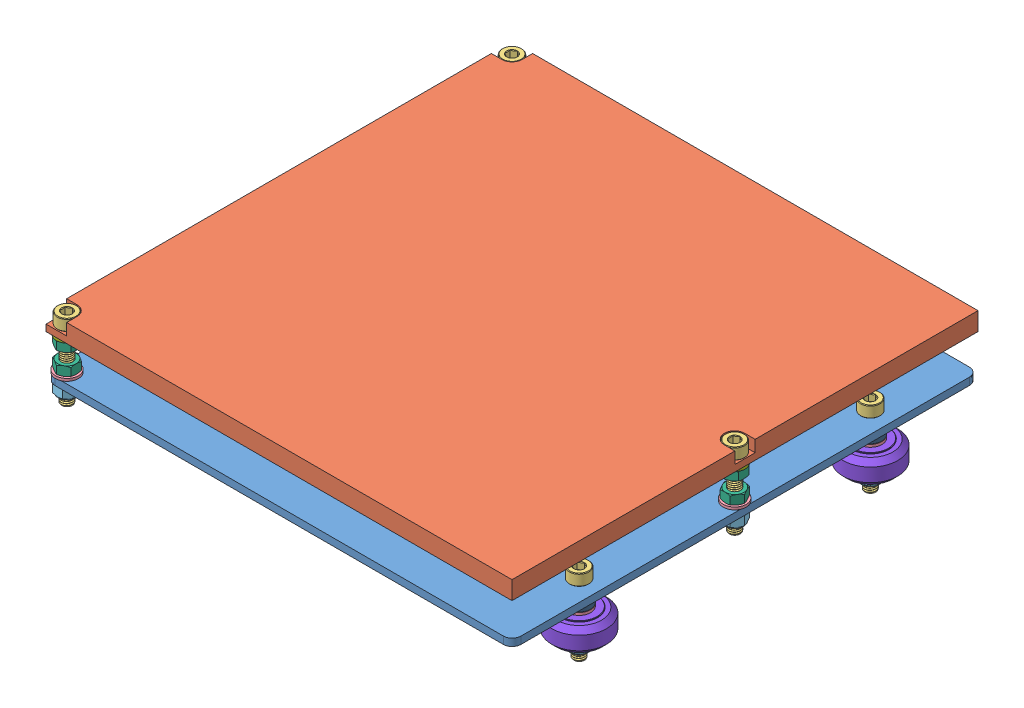
SolidWorks assembly Y-101, configuration Default. Lengths in mm.
Overall size (210.29 53.63 206.16).
50 component instances, 13 part files, 60 mates.
Components (placement in the parent):
- Y-004_rB-1: Y-004_rB [Default] at (-78.9779 0.4223 88.2972) size (203.2 3.17 203.2)
- Y-003-1: Y-003 [Default] at (124.1509 18.8373 -114.9028) x (-1 0 0) z (0 0 -1) size (203.2 7.94 203.2)
- H-017-2: H-017 [91290A194] at (-74.4771 -8.3052 83.7252) x (1 0 0) z (0 -1 0) size (8.5 8.5 35.53)
- H-011-1: H-011 [93475A240] at (-74.4771 4.6973 83.7252) x (1 0 0) z (0 -1 0) size (10 10 1.1)
- H-012-1: H-012 [90576A104] at (-74.4771 0.4223 83.7252) x (-0.837169 0 -0.546944) z (-0.546944 0 0.837169) size (8 5.15 9.24)
- H-016-1: H-016 [92497A300] at (-74.4771 6.6973 83.7252) x (1 0 0) z (0 -1 0) size (8 9.24 4.46)
- H-016-2: H-016 [92497A300] at (-74.4771 15.7373 83.7252) x (1 0 0) z (0 -1 0) size (8 9.24 4.46)
- H-018-1: H-018 [93475A240] at (-74.4771 17.7373 83.7252) x (1 0 0) z (0 1 0) size (9.2 9.2 1.1)
- H-018-2: H-018 [93475A240] at (-74.4771 18.8373 -110.3308) x (1 0 0) z (0 -1 0) size (9.2 9.2 1.1)
- H-016-3: H-016 [92497A300] at (-74.4771 6.6973 -110.3308) x (1 0 0) z (0 -1 0) size (8 9.24 4.46)
- H-016-4: H-016 [92497A300] at (-74.4771 15.7373 -110.3308) x (1 0 0) z (0 -1 0) size (8 9.24 4.46)
- H-012-2: H-012 [90576A104] at (-74.4771 0.4223 -110.3308) x (0.837169 0 -0.546944) z (-0.546944 0 -0.837169) size (8 5.15 9.24)
- H-011-2: H-011 [93475A240] at (-74.4771 3.5973 -110.3308) x (1 0 0) z (0 1 0) size (10 10 1.1)
- H-017-3: H-017 [91290A194] at (-74.4771 -8.3052 -110.3308) x (1 0 0) z (0 -1 0) size (8.5 8.5 35.53)
- H-017-4: H-017 [91290A194] at (119.672 -8.3052 -13.3028) x (1 0 0) z (0 -1 0) size (8.5 8.5 35.53)
- H-011-3: H-011 [93475A240] at (119.672 4.6973 -13.3028) x (1 0 0) z (0 -1 0) size (10 10 1.1)
- H-012-3: H-012 [90576A104] at (119.672 0.4223 -13.3028) x (-0.837169 0 -0.546944) z (-0.546944 0 0.837169) size (8 5.15 9.24)
- H-016-5: H-016 [92497A300] at (119.672 6.6973 -13.3028) x (-0.837169 0 -0.546944) z (0 1 0) size (8 9.24 4.46)
- H-016-6: H-016 [92497A300] at (119.5789 15.7373 -13.3028) x (1 0 0) z (0 -1 0) size (8 9.24 4.46)
- H-018-3: H-018 [93475A240] at (119.5789 18.8373 -13.3028) x (-1 0 0) z (0 -1 0) size (9.2 9.2 1.1)
- H-014-1: H-014 [Default] at (115.3206 -12.1777 50.1972) x (0 1 0) z (0 0 1) size (11 23.9 23.9)
- H-014-4: H-014 [Default] at (-69.4835 -12.1777 50.7192) x (0 -1 0) z (0.98979 0 0.142531) size (11 23.9 23.9)
- H-017-5: H-017 [91290A194] at (115.3206 -26.4027 50.1972) x (1 0 0) z (0 -1 0) size (8.5 8.5 35.53)
- H-002-1: H-002 [Default] at (-70.0765 0.4223 50.1972) x (-0.660682 0 0.750666) z (0.750666 0 0.660682) size (11.55 8.5 10)
- H-003-1: H-003 [Default] at (115.3206 0.4223 50.1972) x (-1 0 0) z (0 -1 0) size (10 10 6)
- H-011-4: H-011 [93475A240] at (115.3206 -6.6777 50.1972) x (-0.837169 0 -0.546944) z (0 1 0) size (10 10 1.1)
- H-012-4: H-012 [90576A104] at (115.3206 -17.6777 50.1972) x (-0.837169 0 -0.546944) z (-0.546944 0 0.837169) size (8 5.15 9.24)
- H-017-6: H-017 [91290A194] at (-69.4835 -26.4027 50.7192) x (0.142531 0 -0.98979) z (0 -1 0) size (8.5 8.5 35.53)
- H-012-5: H-012 [90576A104] at (-69.4835 -17.6777 50.7192) x (-0.861791 0 -0.507263) z (-0.507263 0 0.861791) size (8 5.15 9.24)
- H-011-5: H-011 [93475A240] at (-69.4835 -6.6777 50.7192) x (-0.861791 0 -0.507263) z (0 1 0) size (10 10 1.1)
- H-014-5: H-014 [Default] at (115.3206 -12.1777 -76.8028) x (0 1 0) z (0 0 1) size (11 23.9 23.9)
- H-014-6: H-014 [Default] at (-69.4835 -12.1777 -77.3247) x (0 -1 0) z (-0.98979 0 0.142531) size (11 23.9 23.9)
- H-017-7: H-017 [91290A194] at (115.3206 -26.4027 -76.8028) x (1 0 0) z (0 -1 0) size (8.5 8.5 35.53)
- H-002-2: H-002 [Default] at (-70.0765 0.4223 -76.8028) x (0.660682 0 0.750666) z (0.750666 0 -0.660682) size (11.55 8.5 10)
- H-003-2: H-003 [Default] at (115.3206 -5.5777 -76.8028) x (-1 0 0) z (0 1 0) size (10 10 6)
- H-011-6: H-011 [93475A240] at (115.3206 -5.5777 -76.8028) x (-0.837169 0 0.546944) z (0 -1 0) size (10 10 1.1)
- H-012-6: H-012 [90576A104] at (115.3206 -17.6777 -76.8028) x (0.837169 0 -0.546944) z (-0.546944 0 -0.837169) size (8 5.15 9.24)
- H-017-8: H-017 [91290A194] at (-69.4835 -26.4027 -77.3247) x (0.142531 0 0.98979) z (0 -1 0) size (8.5 8.5 35.53)
- H-012-7: H-012 [90576A104] at (-69.4835 -17.6777 -77.3247) x (0.861791 0 -0.507263) z (-0.507263 0 -0.861791) size (8 5.15 9.24)
- H-011-7: H-011 [93475A240] at (-69.4835 -5.5777 -77.3247) x (-0.861791 0 0.507263) z (0 -1 0) size (10 10 1.1)
- PX-003-1: PX-003 [Default] at (32.6221 -0.8477 9.4772) x (0 0 -1) z (1 0 0) size (8 4 20)
- H-019-1: H-019 [90576A102] at (15.6221 -4.8477 4.4772) x (-0.837169 0 -0.546944) z (-0.546944 0 0.837169) size (5.5 4.1 6.35)
- H-021-1: H-021 [91239A117] at (15.6221 5.2473 4.4772) x (1 0 0) z (0 1 0) size (5.7 5.7 13.97)
- H-021-2: H-021 [91239A117] at (29.6221 5.2473 4.4772) x (1 0 0) z (0 1 0) size (5.7 5.7 13.97)
- H-019-2: H-019 [90576A102] at (29.6221 -4.8477 4.4772) x (-0.837169 0 -0.546944) z (-0.546944 0 0.837169) size (5.5 4.1 6.35)
- PX-003-2: PX-003 [Default] at (12.6221 -0.8477 -36.0828) x (0 0 1) z (-1 0 0) size (8 4 20)
- H-019-3: H-019 [90576A102] at (29.6221 -4.8477 -31.0828) x (0.837169 0 -0.546944) z (-0.546944 0 -0.837169) size (5.5 4.1 6.35)
- H-019-4: H-019 [90576A102] at (15.6221 -4.8477 -31.0828) x (0.837169 0 -0.546944) z (-0.546944 0 -0.837169) size (5.5 4.1 6.35)
- H-021-3: H-021 [91239A117] at (15.6221 5.2473 -31.0828) x (1 0 0) z (0 1 0) size (5.7 5.7 13.97)
- H-021-4: H-021 [91239A117] at (29.6221 5.2473 -31.0828) x (1 0 0) z (0 1 0) size (5.7 5.7 13.97)
Mates (geometry in assembly coordinates):
- Parallel1: parallel aligned: plane of Y-004_rB-1 through (-78.9779 3.5973 88.2972) normal (-1 0 0); plane of Y-003-1 through (-79.0491 26.7748 -114.9028) normal (-1 0 0)
- Coincident2: coincident aligned: plane of Y-004_rB-1 through (-78.9779 3.5973 88.2972) normal (0 0 1); plane of Y-003-1 through (124.1509 26.7748 88.2972) normal (0 0 1)
- Concentric1: concentric anti-aligned: cylinder of Y-004_rB-1 through (-74.4771 3.5983 83.7252) axis (0 -1 0) radius 2.625; cylinder of Y-003-1 through (-74.4771 18.8363 83.7252) axis (0 1 0) radius 2.6098
- Concentric2: concentric anti-aligned: circle of Y-004_rB-1; circle of H-017-2
- Concentric5: concentric anti-aligned: circle of Y-004_rB-1; circle of H-011-1
- Coincident3: coincident anti-aligned: plane of Y-003-1 through (-74.4771 21.6948 83.7252) normal (0 1 0); plane of H-017-2 through (-74.4771 21.6948 83.7252) normal (0 -1 0)
- Coincident4: coincident anti-aligned: plane of Y-004_rB-1 through (-78.9779 3.5973 88.2972) normal (0 1 0); plane of H-011-1 through (-74.4771 3.5973 83.7252) normal (0 -1 0)
- Coincident5: coincident anti-aligned: plane of H-011-1 through (-74.4771 4.6973 83.7252) normal (0 1 0); plane of H-016-1 through (-78.4771 4.6973 86.0346) normal (0 -1 0)
- Concentric6: concentric anti-aligned: circle of H-011-1; circle of H-016-1
- Coincident6: coincident anti-aligned: plane of Y-004_rB-1 through (-78.9779 0.4223 88.2972) normal (0 -1 0); plane of H-012-1 through (-67.3391 0.4223 80.1129) normal (0 1 0)
- Concentric7: concentric anti-aligned: circle of Y-004_rB-1; circle of H-012-1
- Concentric8: concentric aligned: circle of Y-003-1; circle of H-016-2
- Distance1: distance = 15.24 mm anti-aligned: plane of Y-003-1 through (124.1509 18.8373 -114.9028) normal (0 -1 0); plane of Y-004_rB-1 through (-78.9779 3.5973 88.2972) normal (0 1 0)
- Concentric9: concentric aligned: circle of Y-003-1; circle of H-018-1
- Coincident7: coincident anti-aligned: plane of Y-003-1 through (124.1509 18.8373 -114.9028) normal (0 -1 0); plane of H-018-1 through (-74.4771 18.8373 83.7252) normal (0 1 0)
- Coincident8: coincident anti-aligned: plane of H-016-2 through (-78.4771 17.7373 86.0346) normal (0 1 0); plane of H-018-1 through (-74.4771 17.7373 83.7252) normal (0 -1 0)
- Concentric10: concentric aligned: cylinder of Y-004_rB-1 through (119.672 3.5983 -13.3028) axis (0 -1 0) radius 2.625; circle of H-017-4
- Coincident9: coincident anti-aligned: plane of Y-003-1 through (119.5789 21.6948 -13.3028) normal (0 1 0); plane of H-017-4 through (119.672 21.6948 -13.3028) normal (0 -1 0)
- Concentric11: concentric anti-aligned: circle of Y-003-1; circle of H-018-3
- Coincident10: coincident anti-aligned: plane of Y-003-1 through (124.1509 18.8373 -114.9028) normal (0 -1 0); plane of H-018-3 through (119.5789 18.8373 -13.3028) normal (0 1 0)
- Concentric12: concentric anti-aligned: circle of H-017-4; circle of H-012-3
- Coincident11: coincident anti-aligned: plane of Y-004_rB-1 through (-78.9779 0.4223 88.2972) normal (0 -1 0); plane of H-012-3 through (126.8101 0.4223 -16.9151) normal (0 1 0)
- Coincident12: coincident anti-aligned: plane of Y-004_rB-1 through (-78.9779 3.5973 88.2972) normal (0 1 0); plane of H-011-3 through (119.672 3.5973 -13.3028) normal (0 -1 0)
- Concentric13: concentric anti-aligned: circle of Y-004_rB-1; circle of H-011-3
- Coincident13: coincident anti-aligned: plane of H-011-3 through (119.672 4.6973 -13.3028) normal (0 1 0); plane of H-016-5 through (121.7576 4.6973 -9.1816) normal (0 -1 0)
- Concentric14: concentric aligned: circle of H-011-3; circle of H-016-5
- Concentric15: concentric aligned: circle of H-016-6; circle of H-018-3
- Coincident14: coincident anti-aligned: plane of H-016-6 through (115.5789 17.7373 -10.9934) normal (0 1 0); plane of H-018-3 through (119.5789 17.7373 -13.3028) normal (0 -1 0)
- Concentric16: concentric anti-aligned: circle of Y-004_rB-1; circle of H-017-5
- Coincident15: coincident anti-aligned: plane of Y-004_rB-1 through (-78.9779 3.5973 88.2972) normal (0 1 0); plane of H-017-5 through (115.3206 3.5973 50.1972) normal (0 -1 0)
- Concentric17: concentric anti-aligned: circle of H-014-1; circle of H-017-5
- Concentric18: concentric aligned: circle of Y-004_rB-1; circle of H-003-1
- Coincident16: coincident anti-aligned: plane of Y-004_rB-1 through (-78.9779 0.4223 88.2972) normal (0 -1 0); plane of H-003-1 through (112.5706 0.4223 50.1972) normal (0 1 0)
- Coincident17: coincident anti-aligned: plane of H-003-1 through (110.5206 -5.5777 50.1972) normal (0 -1 0); plane of H-011-4 through (115.3206 -5.5777 50.1972) normal (0 1 0)
- Concentric20: concentric aligned: circle of H-003-1; circle of H-011-4
- Concentric21: concentric anti-aligned: circle of H-014-1; circle of H-011-4
- Coincident18: coincident anti-aligned: plane of H-014-1 through (115.3206 -6.6777 50.1972) normal (0 1 0); plane of H-011-4 through (115.3206 -6.6777 50.1972) normal (0 -1 0)
- Concentric22: concentric anti-aligned: circle of H-014-1; circle of H-012-4
- Coincident19: coincident anti-aligned: plane of H-014-1 through (115.3206 -17.6777 50.1972) normal (0 -1 0); plane of H-012-4 through (122.4586 -17.6777 46.5849) normal (0 1 0)
- Coincident21: coincident anti-aligned: plane of Y-004_rB-1 through (-78.9779 3.5973 88.2972) normal (0 1 0); plane of H-017-6 through (-69.4835 3.5973 50.7192) normal (0 -1 0)
- Concentric24: concentric anti-aligned: circle of Y-004_rB-1; circle of H-002-1
- Coincident22: coincident anti-aligned: plane of Y-004_rB-1 through (-78.9779 0.4223 88.2972) normal (0 -1 0); plane of H-002-1 through (-70.0765 0.4223 50.1972) normal (0 1 0)
- Concentric25: concentric anti-aligned: circle of H-014-4; circle of H-002-1
- Concentric26: concentric anti-aligned: circle of H-002-1; circle of H-017-6
- Concentric27: concentric aligned: circle of H-002-1; circle of H-011-5
- Coincident23: coincident anti-aligned: plane of H-002-1 through (-70.0765 -5.5777 50.1972) normal (0 -1 0); plane of H-011-5 through (-69.4835 -5.5777 50.7192) normal (0 1 0)
- Coincident24: coincident anti-aligned: plane of H-014-4 through (-69.4835 -6.6777 50.7192) normal (0 1 0); plane of H-011-5 through (-69.4835 -6.6777 50.7192) normal (0 -1 0)
- Coincident25: coincident anti-aligned: plane of H-014-4 through (-69.4835 -17.6777 50.7192) normal (0 -1 0); plane of H-012-5 through (-62.5219 -17.6777 46.7775) normal (0 1 0)
- Concentric28: concentric aligned: circle of H-017-6; circle of H-012-5
- Concentric29: concentric aligned: circle of Y-004_rB-1; circle of PX-003-1
- Concentric30: concentric aligned: circle of Y-004_rB-1; circle of PX-003-1
- Distance2: distance = 1.27 mm anti-aligned: plane of PX-003-1 through (32.6221 -0.8477 9.4772) normal (0 1 0); plane of Y-004_rB-1 through (-78.9779 0.4223 88.2972) normal (0 -1 0)
- Coincident28: coincident anti-aligned: plane of PX-003-1 through (32.6221 -4.8477 9.4772) normal (0 -1 0); plane of H-019-1 through (14.1882 -4.8477 1.6439) normal (0 1 0)
- Concentric32: concentric aligned: circle of PX-003-1; circle of H-019-1
- Coincident29: coincident anti-aligned: plane of Y-004_rB-1 through (-78.9779 3.5973 88.2972) normal (0 1 0); plane of H-021-1 through (15.6221 3.5973 7.3272) normal (0 -1 0)
- Concentric33: concentric aligned: circle of Y-004_rB-1; cylinder of H-021-1 through (15.6221 5.2473 4.4772) axis (0 1 0) radius 2.85
- Concentric34: concentric aligned: circle of Y-004_rB-1; circle of H-021-2
- Coincident30: coincident anti-aligned: plane of Y-004_rB-1 through (-78.9779 3.5973 88.2972) normal (0 1 0); plane of H-021-2 through (29.6221 3.5973 7.3272) normal (0 -1 0)
- Coincident31: coincident anti-aligned: plane of PX-003-1 through (32.6221 -4.8477 9.4772) normal (0 -1 0); plane of H-019-2 through (28.1882 -4.8477 1.6439) normal (0 1 0)
- Concentric36: concentric aligned: circle of PX-003-1; circle of H-019-2
